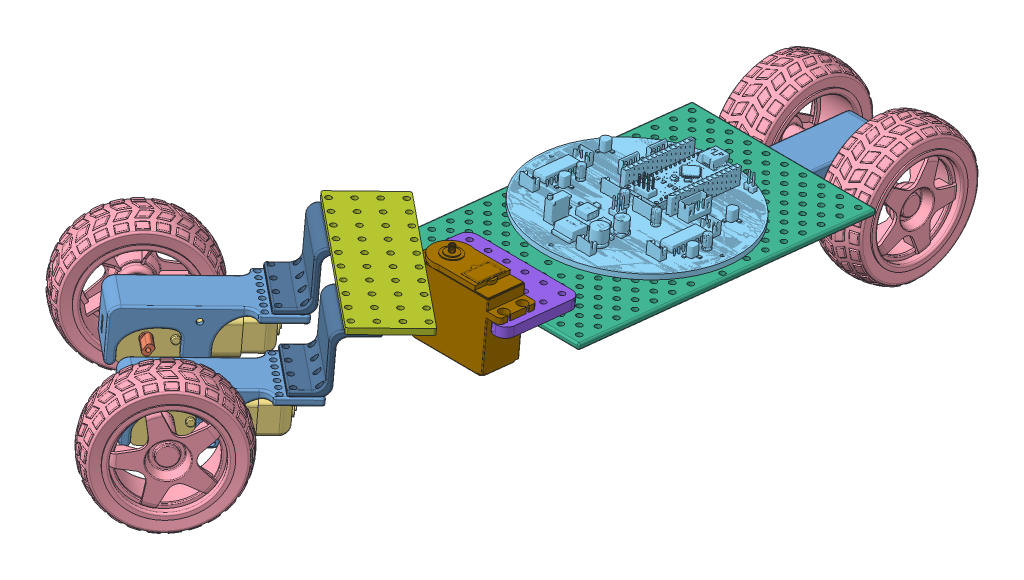
SolidWorks assembly example_1, configuration Défaut. Lengths in mm.
Overall size (189.56 140.02 448.92).
23 component instances, 10 part files, 38 mates.
Components (placement in the parent):
- dc_motor_2-2: dc_motor_2 [Défaut] at (-1533.4893 85.5999 385.8643) x (0.639007 -0.075788 -0.765459) z (-0.769201 -0.06296 -0.635897) size (77.2 26.55 37.5)
  - DC_motor_adapter_2-1: DC_motor_adapter_2 [Défaut] at (-41.277 -6.8261 92.2) size (77.2 26.55 35)
  - axis_gear_motor-1: axis_gear_motor [Default] at (-31.3629 2.3802 82.2) x (0.569545 -0.82196 0) z (0 0 1) size (5.6 5.6 37.5)
  - body_gear_motor-1: body_gear_motor [Default] at (-18.427 6.4239 82.2) x (0 1 0) z (0 0 1) size (22.6 68.6 21.65)
- Wheel D65x25-2: Wheel D65x25 [По умолчанию] at (-1581.4923 78.5479 379.8381) x (-0.363943 -0.774796 0.516949) z (0.769201 0.06296 0.635897) size (69.23 69.36 30)
- dc_motor_2-3: dc_motor_2 [Défaut] at (-1664.068 43.3384 39.9956) x (-0.006358 0.098526 0.995114) z (0.99998 0.000626 0.006327) size (77.2 26.55 37.5)
  - DC_motor_adapter_2-1: DC_motor_adapter_2 [Défaut] at (-41.277 -6.8261 92.2) size (77.2 26.55 35)
  - axis_gear_motor-1: axis_gear_motor [Default] at (-31.3629 2.3802 82.2) x (0.569545 -0.82196 0) z (0 0 1) size (5.6 5.6 37.5)
  - body_gear_motor-1: body_gear_motor [Default] at (-18.427 6.4239 82.2) x (0 1 0) z (0 0 1) size (22.6 68.6 21.65)
- Wheel D65x25-3: Wheel D65x25 [По умолчанию] at (-1540.7082 34.5078 16.0058) x (-0.003621 0.874076 0.485776) z (0.99998 0.000626 0.006327) size (69.23 69.36 30)
- Wheel D65x25-4: Wheel D65x25 [По умолчанию] at (-1622.7065 34.4565 15.487) x (0.006358 -0.098526 -0.995114) z (-0.99998 -0.000626 -0.006327) size (69.23 69.36 30)
- pcb-2: pcb [Défaut] at (-533.2142 149.2132 937.541) x (-0.99998 -0.000626 -0.006327) z (0 0.995134 -0.098528) size (100 100 22.63)
- base_plate_2-1: base_plate_2 [Défaut] at (-1631.9222 52.9716 47.7116) x (-0.006358 0.098526 0.995114) z (0 0.995134 -0.098528) size (160 100 3)
- plate_L100l35-1: plate_L100l35 [Défaut] at (-1609.7384 111.2563 220.4848) x (0.769201 0.06296 0.635897) z (0 -0.995134 0.098528) size (100 35 3)
- dc_motor_2-4: dc_motor_2 [Défaut] at (-1579.6413 81.8223 347.7105) x (0.639007 -0.075788 -0.765459) z (-0.769201 -0.06296 -0.635897) size (77.2 26.55 37.5)
  - DC_motor_adapter_2-1: DC_motor_adapter_2 [Défaut] at (-41.277 -6.8261 92.2) size (77.2 26.55 35)
  - axis_gear_motor-1: axis_gear_motor [Default] at (-31.3629 2.3802 82.2) x (0.569545 -0.82196 0) z (0 0 1) size (5.6 5.6 37.5)
  - body_gear_motor-1: body_gear_motor [Default] at (-18.427 6.4239 82.2) x (0 1 0) z (0 0 1) size (22.6 68.6 21.65)
- Wheel D65x25-5: Wheel D65x25 [По умолчанию] at (-1690.7188 69.6076 289.5407) x (-0.363943 -0.774796 0.516949) z (-0.769201 -0.06296 -0.635897) size (69.23 69.36 30)
- support_1-1: support_1 [Défaut] at (-1549.2583 77.8527 217.8156) x (-0.99998 -0.000626 -0.006327) z (0 -0.995134 0.098528) size (61 41 5)
- MG996R-1: MG996R [Default] at (-1583.0072 50.8941 219.567) x (-0.99998 -0.000626 -0.006327) z (0.006358 -0.098526 -0.995114) size (54 41.75 20)
- rehausseur_zigzag_H5L35l35-1: rehausseur_zigzag_H5L35l35 [Défaut] at (-1633.714 84.6313 256.0539) x (0.639007 -0.075788 -0.765459) z (0.769201 0.06296 0.635897) size (35 30 35)
- rehausseur_zigzag_H5L35l35-2: rehausseur_zigzag_H5L35l35 [Défaut] at (-1587.5619 88.4089 294.2078) x (0.639007 -0.075788 -0.765459) z (0.769201 0.06296 0.635897) size (35 30 35)
Mates (geometry in assembly coordinates):
- Coaxiale12: concentric: cylinder of dc_motor_2-2/axis_gear_motor-1 through (-1627.452 74.7861 341.8432) axis (0.769201 0.06296 0.635897) radius 1; cylinder of Wheel D65x25-2 through (-1581.4923 78.5479 379.8381) axis (0.769201 0.06296 0.635897) radius 2.75
- Parallèle3: parallel: plane of dc_motor_2-2/axis_gear_motor-1 through (-1627.4229 78.0805 341.4818) normal (-0.525238 0.629068 0.57306); plane of Wheel D65x25-2 through (383018.1954 31559.7815 318329.5388) normal (0.525238 -0.629068 -0.57306)
- Coïncidente10: coincident: plane of dc_motor_2-2/axis_gear_motor-1 through (-1604.5683 76.6591 360.7612) normal (0.769201 0.06296 0.635897); plane of Wheel D65x25-2 through (-1604.5683 76.6591 360.7612) normal (-0.769201 -0.06296 -0.635897)
- Coaxiale15: concentric: cylinder of dc_motor_2-3/axis_gear_motor-1 through (-1562.9577 34.4939 15.865) axis (-0.99998 -0.000626 -0.006327) radius 1; cylinder of Wheel D65x25-4 through (-1622.7065 34.4565 15.487) axis (-0.99998 -0.000626 -0.006327) radius 2.75
- Coaxiale16: concentric: cylinder of dc_motor_2-3/axis_gear_motor-1 through (-1562.9577 34.4939 15.865) axis (-0.99998 -0.000626 -0.006327) radius 1; cylinder of Wheel D65x25-3 through (-1540.7082 34.5078 16.0058) axis (0.99998 0.000626 0.006327) radius 2.75
- Parallèle4: parallel: plane of dc_motor_2-3/axis_gear_motor-1 through (-1562.9774 35.9989 18.8179) normal (-0.005226 -0.485789 0.874061); plane of Wheel D65x25-3 through (498449.1952 348.6015 3177.9432) normal (-0.005226 -0.485789 0.874061)
- Parallèle5: parallel: plane of dc_motor_2-3/DC_motor_adapter_2-1 through (-1593.792 24.5947 30.0637) normal (0 -0.995134 0.098528); plane of Wheel D65x25-4 through (-501612.6005 -276.9715 -3148.2011) normal (0 -0.995134 0.098528)
- Coïncidente15: coincident: plane of dc_motor_2-3/axis_gear_motor-1 through (-1592.7071 34.4753 15.6768) normal (-0.99998 -0.000626 -0.006327); plane of Wheel D65x25-4 through (-1592.7071 34.4753 15.6768) normal (0.99998 0.000626 0.006327)
- Coïncidente16: coincident: plane of dc_motor_2-3/axis_gear_motor-1 through (-1570.7076 34.489 15.816) normal (0.99998 0.000626 0.006327); plane of Wheel D65x25-3 through (-1570.7076 34.489 15.816) normal (-0.99998 -0.000626 -0.006327)
- Tangent6: tangent: torus of Wheel D65x25-3; plane of assembly through (0 0 0) normal (0 1 0)
- Coaxiale41: concentric: cylinder of dc_motor_2-3/DC_motor_adapter_2-1 through (-1581.9868 58.4663 57.5357) axis (0 -0.995134 0.098528) radius 1.5; cylinder of base_plate_2-1 through (-1581.9868 53.9882 57.9791) axis (0 0.995134 -0.098528) radius 1.5
- Coaxiale42: concentric: cylinder of dc_motor_2-3/DC_motor_adapter_2-1 through (-1591.9866 58.46 57.4724) axis (0 -0.995134 0.098528) radius 1.5; cylinder of base_plate_2-1 through (-1591.9866 53.9819 57.9158) axis (0 0.995134 -0.098528) radius 1.5
- Coïncidente40: coincident: plane of dc_motor_2-3/DC_motor_adapter_2-1 through (-1571.6074 48.1124 -1.3659) normal (0 0.995134 -0.098528); plane of base_plate_2-1 through (-1631.9222 52.9716 47.7116) normal (0 -0.995134 0.098528)
- Coaxiale47: concentric: cylinder of pcb-2 through (-1582.7307 94.8722 171.5009) axis (0 -0.995134 0.098528) radius 1.5; cylinder of base_plate_2-1 through (-1582.7307 65.5157 174.4074) axis (0 0.995134 -0.098528) radius 1.5
- Coaxiale48: concentric: cylinder of pcb-2 through (-1629.4309 90.212 124.4331) axis (0 -0.995134 0.098528) radius 1.5; cylinder of base_plate_2-1 through (-1629.4309 60.8556 127.3397) axis (0 0.995134 -0.098528) radius 1.5
- Distance5: distance = 5 mm: plane of pcb-2 through (-1582.4318 68.8461 126.8489) normal (0 -0.995134 0.098528); plane of base_plate_2-1 through (-1631.9222 55.957 47.416) normal (0 0.995134 -0.098528)
- Tangent8: tangent: torus of Wheel D65x25-3; plane of assembly through (0 0 0) normal (0 1 0)
- Coaxiale61: concentric: cylinder of dc_motor_2-4/axis_gear_motor-1 through (-1673.6041 71.0085 303.6894) axis (0.769201 0.06296 0.635897) radius 1; cylinder of Wheel D65x25-5 through (-1690.7188 69.6076 289.5407) axis (-0.769201 -0.06296 -0.635897) radius 2.75
- Parallèle13: parallel: plane of dc_motor_2-4/axis_gear_motor-1 through (-1673.575 74.3029 303.3279) normal (-0.525238 0.629068 0.57306); plane of Wheel D65x25-5 through (-386290.4065 -31411.626 -317660.16) normal (-0.525238 0.629068 0.57306)
- Coïncidente55: coincident: plane of Wheel D65x25-5 through (-1667.6428 71.4964 308.6176) normal (0.769201 0.06296 0.635897); plane of dc_motor_2-4/axis_gear_motor-1 through (-1667.6428 71.4964 308.6176) normal (-0.769201 -0.06296 -0.635897)
- Coaxiale77: concentric: cylinder of support_1-1 through (-1606.975 77.255 211.7793) axis (0 -0.995134 0.098528) radius 1.5; cylinder of MG996R-1 through (-1606.975 50.3864 214.4395) axis (0 0.995134 -0.098528) radius 2.5
- Coaxiale78: concentric: cylinder of support_1-1 through (-1559.0395 78.2704 222.0341) axis (0 -0.995134 0.098528) radius 1.5; cylinder of MG996R-1 through (-1559.0395 51.4018 224.6944) axis (0 0.995134 -0.098528) radius 2.5
- Coïncidente63: coincident: plane of support_1-1 through (-1549.2583 77.8527 217.8156) normal (0 0.995134 -0.098528); plane of MG996R-1 through (-1556.0714 78.7649 227.0287) normal (0 -0.995134 0.098528)
- Coïncidente64: coincident: cylinder of base_plate_2-1 through (-1557.9092 68.2901 202.4288) axis (0 0.995134 -0.098528) radius 1.5; circle of support_1-1
- Coaxiale79: concentric: cylinder of base_plate_2-1 through (-1607.9082 68.2588 202.1125) axis (0 0.995134 -0.098528) radius 1.5; cylinder of support_1-1 through (-1607.9082 76.2199 201.3242) axis (0 -0.995134 0.098528) radius 1.5
- Coïncidente65: coincident: plane of base_plate_2-1 through (-1631.9222 55.957 47.416) normal (0 0.995134 -0.098528); plane of support_1-1 through (-1549.2583 72.877 218.3082) normal (0 -0.995134 0.098528)
- Coaxiale84: concentric: cylinder of dc_motor_2-2/DC_motor_adapter_2-1 through (-1570.2121 92.8551 323.8896) axis (0 -0.995134 0.098528) radius 1.5; cylinder of rehausseur_zigzag_H5L35l35-2 through (-1570.2121 83.4013 324.8257) axis (0 0.995134 -0.098528) radius 1.5
- Coaxiale85: concentric: cylinder of dc_motor_2-2/DC_motor_adapter_2-1 through (-1586.8981 90.2084 297.1581) axis (0 -0.995134 0.098528) radius 1.5; cylinder of rehausseur_zigzag_H5L35l35-2 through (-1586.8981 80.7546 298.0942) axis (0 0.995134 -0.098528) radius 1.5
- Coïncidente66: coincident: plane of dc_motor_2-2/DC_motor_adapter_2-1 through (-1630.7859 91.7064 357.9607) normal (0 0.995134 -0.098528); plane of rehausseur_zigzag_H5L35l35-2 through (-1569.8866 88.7238 327.8364) normal (0 -0.995134 0.098528)
- Coaxiale86: concentric: cylinder of dc_motor_2-4/DC_motor_adapter_2-1 through (-1609.9741 88.3196 278.0812) axis (0 -0.995134 0.098528) radius 1.5; cylinder of rehausseur_zigzag_H5L35l35-1 through (-1609.9741 78.8658 279.0172) axis (0 0.995134 -0.098528) radius 1.5
- Coaxiale87: concentric: cylinder of dc_motor_2-4/DC_motor_adapter_2-1 through (-1633.0502 86.4308 259.0043) axis (0 -0.995134 0.098528) radius 1.5; cylinder of rehausseur_zigzag_H5L35l35-1 through (-1633.0502 76.977 259.9403) axis (0 0.995134 -0.098528) radius 1.5
- Coïncidente67: coincident: plane of dc_motor_2-4/DC_motor_adapter_2-1 through (-1676.938 87.9288 319.8069) normal (0 0.995134 -0.098528); plane of rehausseur_zigzag_H5L35l35-1 through (-1616.0387 84.9462 289.6826) normal (0 -0.995134 0.098528)
- Coaxiale88: concentric: cylinder of plate_L100l35-1 through (-1626.6601 114.0342 248.5417) axis (0 -0.995134 0.098528) radius 1.5; cylinder of rehausseur_zigzag_H5L35l35-1 through (-1626.6601 76.2191 252.2857) axis (0 0.995134 -0.098528) radius 1.5
- Coaxiale89: concentric: cylinder of plate_L100l35-1 through (-1597.194 115.1651 259.964) axis (0 -0.995134 0.098528) radius 1.5; cylinder of rehausseur_zigzag_H5L35l35-1 through (-1597.194 77.35 263.7081) axis (0 0.995134 -0.098528) radius 1.5
- Coïncidente68: coincident: plane of plate_L100l35-1 through (-1609.7384 108.2709 220.7803) normal (0 -0.995134 0.098528); plane of rehausseur_zigzag_H5L35l35-1 through (-1593.6735 112.1477 259.9357) normal (0 0.995134 -0.098528)
- Coaxiale90: concentric: cylinder of plate_L100l35-1 through (-1557.432 119.7006 305.7724) axis (0 -0.995134 0.098528) radius 1.5; cylinder of rehausseur_zigzag_H5L35l35-2 through (-1557.432 81.8855 309.5165) axis (0 0.995134 -0.098528) radius 1.5
- Coaxiale91: concentric: cylinder of plate_L100l35-1 through (-1574.118 117.0539 279.0409) axis (0 -0.995134 0.098528) radius 1.5; cylinder of rehausseur_zigzag_H5L35l35-2 through (-1574.118 79.2388 282.785) axis (0 0.995134 -0.098528) radius 1.5
- Coïncidente69: coincident: plane of plate_L100l35-1 through (-1609.7384 108.2709 220.7803) normal (0 -0.995134 0.098528); plane of rehausseur_zigzag_H5L35l35-2 through (-1547.5214 115.9253 298.0895) normal (0 0.995134 -0.098528)
